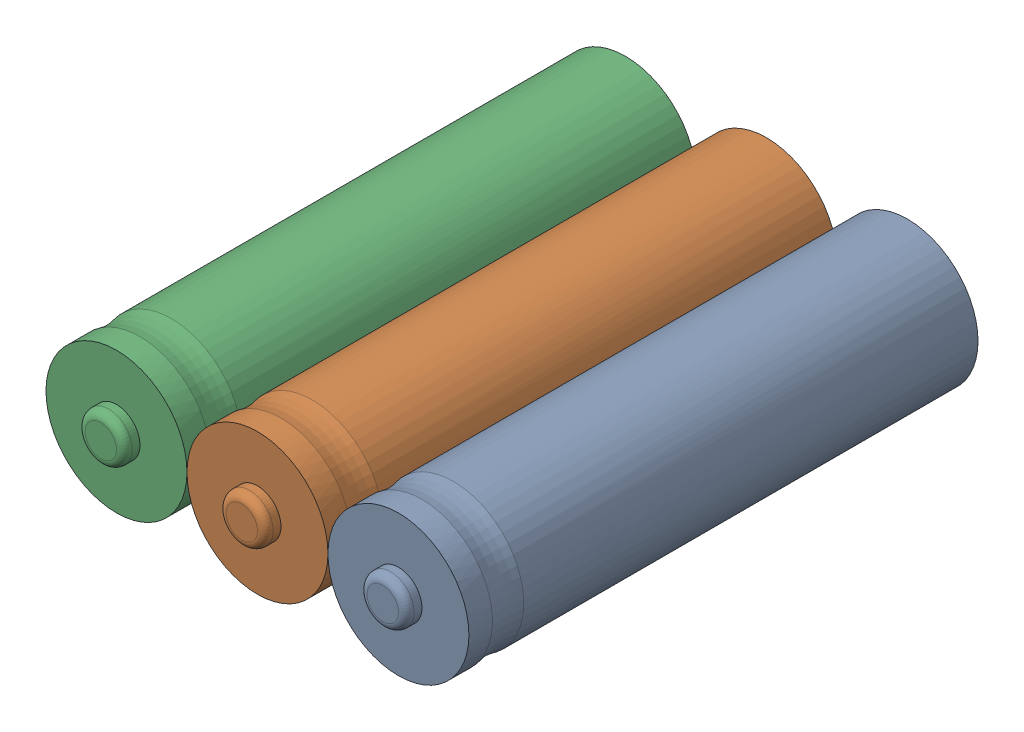
SolidWorks assembly pack bateria, configuration Valor predeterminado. Lengths in mm.
Overall size (54 18 67.4).
3 component instances, 1 part files, 6 mates.
Components (placement in the parent):
- EXA210-1: EXA210 [Valor predeterminado] at (12.4711 1 4.525) size (18 18 67.4)
- EXA210-2: EXA210 [Valor predeterminado] at (-5.5289 1 4.525) size (18 18 67.4)
- EXA210-3: EXA210 [Valor predeterminado] at (-23.5289 1 4.525) size (18 18 67.4)
Mates (geometry in assembly coordinates):
- Tangente1: tangent anti-aligned: cylinder of EXA210-1 through (12.4711 1 32.1036) axis (0 0 -1) radius 9; cylinder of EXA210-2 through (-5.5289 1 37.025) axis (0 0 -1) radius 9
- Tangente3: tangent aligned: cylinder of EXA210-3 through (-23.5289 1 37.025) axis (0 0 -1) radius 9
- Tangente4: tangent aligned: cylinder of EXA210-2 through (-5.5289 1 37.025) axis (0 0 -1) radius 9
- Tangente5: tangent aligned: cylinder of EXA210-1 through (12.4711 1 37.025) axis (0 0 -1) radius 9
- Coincidente1: coincident aligned: plane of EXA210-2 through (-5.5289 1 37.025) normal (0 0 1); plane of EXA210-3 through (-23.5289 1 37.025) normal (0 0 1)
- Coincidente2: coincident aligned: plane of EXA210-1 through (12.4711 1 37.025) normal (0 0 1); plane of EXA210-2 through (-5.5289 1 37.025) normal (0 0 1)
